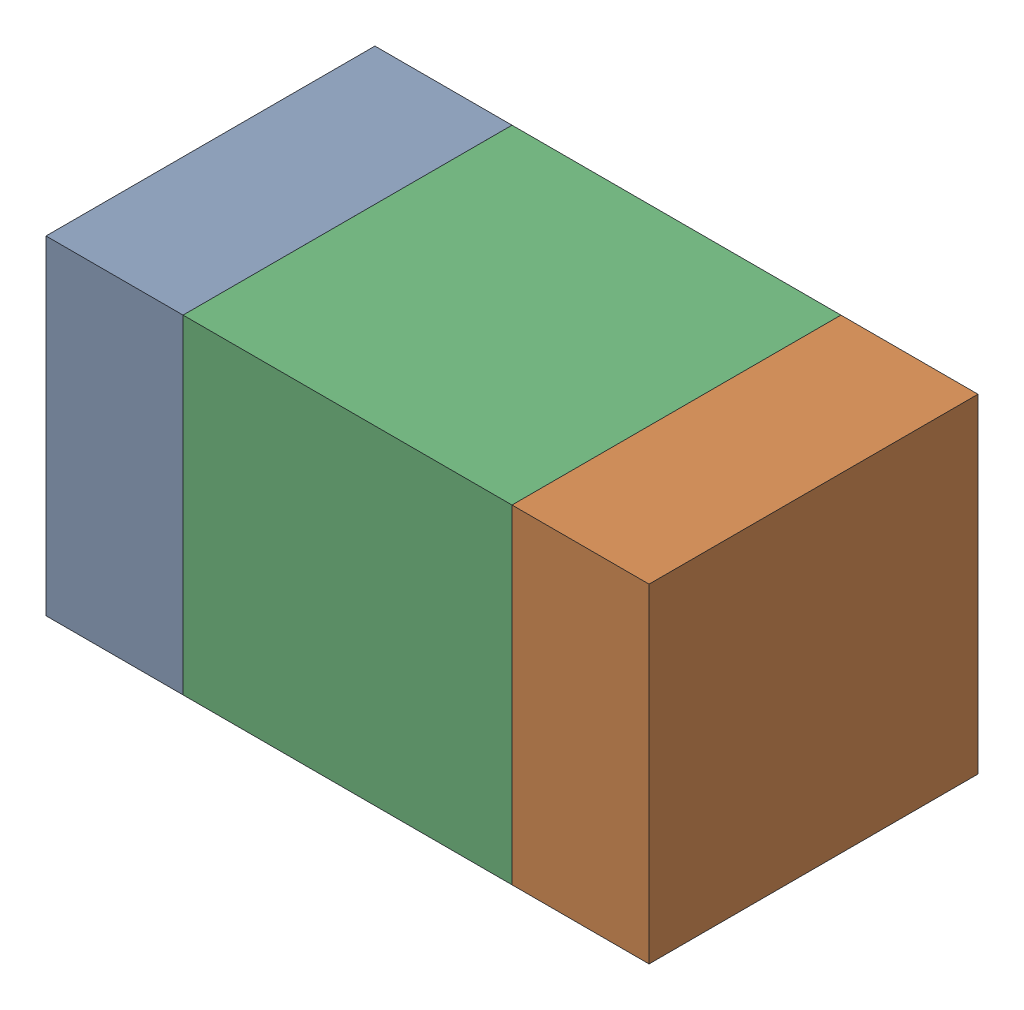
SolidWorks assembly C105_1PCB, configuration Default. Lengths in mm.
Overall size (1.1 0.6 0.6).
6 component instances, 2 part files, 0 mates.
Components (placement in the parent):
- 854785160-1: 854785160 [Default] at (106.575 106.3 0) size (0.25 0.6 0.6)
  - Extruded_19-1: Extruded_19 [Default] at origin size (0.25 0.6 0.6)
- 854785160-2: 854785160 [Default] at (107.425 106.3 0) size (0.25 0.6 0.6)
  - Extruded_19-1: Extruded_19 [Default] at origin size (0.25 0.6 0.6)
- 761606048-1: 761606048 [Default] at (107 106.3 0) size (0.6 0.6 0.6)
  - Extruded_9-1: Extruded_9 [Default] at origin size (0.6 0.6 0.6)
